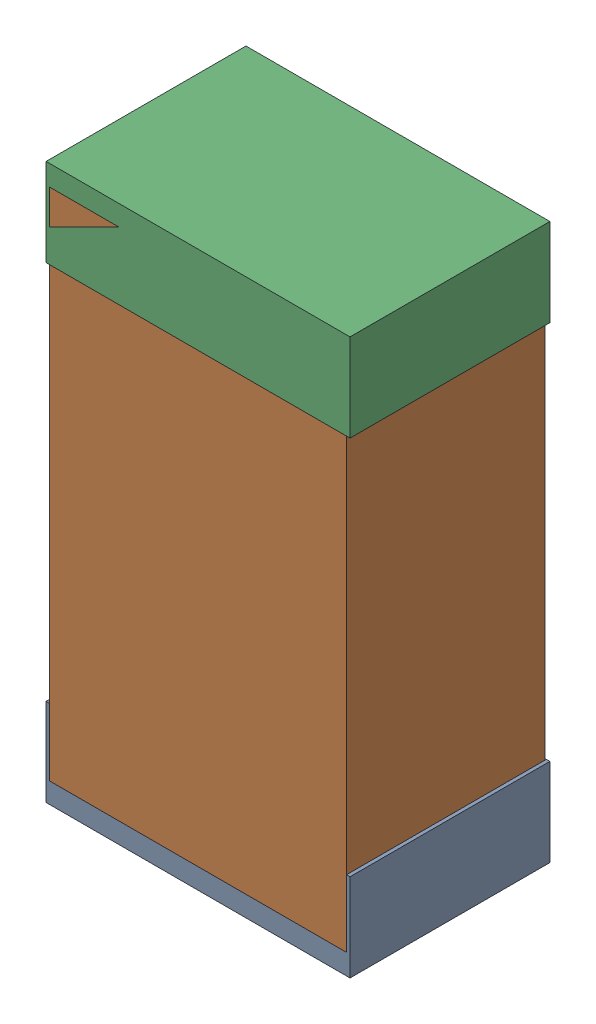
SolidWorks assembly R53Kanaloa_v2.0.0_Motor, configuration Default. Lengths in mm.
Overall size (1.3 2.38 0.85).
6 component instances, 2 part files, 0 mates.
Components (placement in the parent):
- 330415056-1: 330415056 [Default] at (95.504 152.67 -1.9574) size (1.3 0.38 0.85)
  - Extruded_2-1: Extruded_2 [Default] at origin size (1.3 0.38 0.85)
- 334787376-1: 334787376 [Default] at (95.504 153.67 -1.9524) size (1.27 2.2 0.85)
  - Extruded_16-1: Extruded_16 [Default] at origin size (1.27 2.2 0.85)
- 330415056-2: 330415056 [Default] at (95.504 154.67 -1.9574) size (1.3 0.38 0.85)
  - Extruded_2-1: Extruded_2 [Default] at origin size (1.3 0.38 0.85)
